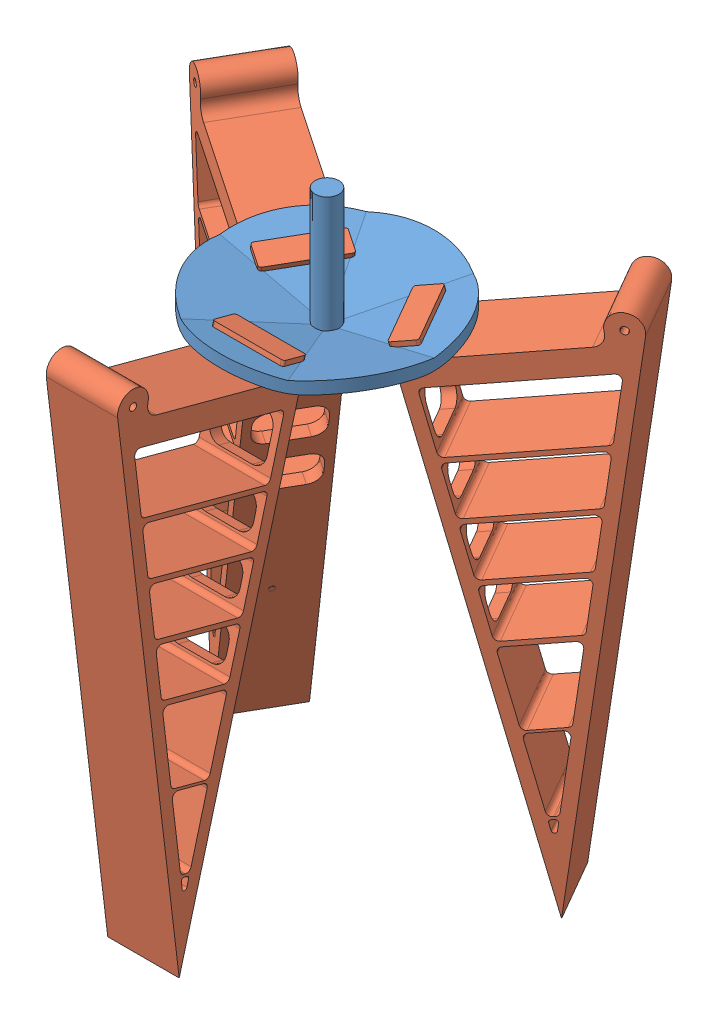
SolidWorks assembly Assem1, configuration Default. Lengths in mm.
Overall size (283.23 241.86 246.25).
4 component instances, 2 part files, 9 mates.
Components (placement in the parent):
- gripper hand-1: gripper hand [Default] at (12.3889 -3.2286 -6.0425) size (90 53.44 90)
- flexable hand-1: flexable hand [Default] at (27.3889 -1.6143 19.3005) x (0 -0.258819 -0.965926) z (0 0.965926 -0.258819) size (81.6 30 211.5)
- flexable hand-2: flexable hand [Default] at (-16.2222 -1.8732 -5.2406) x (0.836516 -0.258819 0.482963) z (0.224144 0.965926 0.12941) size (81.6 30 211.5)
- flexable hand-3: flexable hand [Default] at (26.0001 -1.8732 -31.2214) x (-0.836516 -0.258819 0.482963) z (-0.224144 0.965926 0.12941) size (81.6 30 211.5)
Mates (geometry in assembly coordinates):
- Coincident18: coincident anti-aligned: plane of gripper hand-1 through (36.2584 -15.1704 -37.144) normal (-0.836516 -0.258819 0.482963); plane of flexable hand-3 through (57.2515 5.027 10.041) normal (0.836516 0.258819 -0.482963)
- Coincident19: coincident anti-aligned: plane of gripper hand-1 through (47.0758 -16.4645 -8.7484) normal (-0.5 0 -0.866025); plane of flexable hand-3 through (41.0001 -1.8732 -5.2406) normal (0.5 0 0.866025)
- Coincident20: coincident anti-aligned: plane of gripper hand-1 through (12.3889 -3.2286 -6.0425) normal (-0.224144 0.965926 0.12941); plane of flexable hand-3 through (58.9246 5.5447 9.0751) normal (0.224144 -0.965926 -0.12941)
- Coincident22: coincident anti-aligned: plane of gripper hand-1 through (-2.6111 -12.3467 24.2468) normal (1 0 0); plane of flexable hand-1 through (-2.6111 -1.6143 19.3005) normal (-1 0 0)
- Coincident23: coincident anti-aligned: plane of gripper hand-1 through (27.3889 -12.3467 24.2468) normal (0 0.258819 0.965926); plane of flexable hand-1 through (-23.9711 -1.0967 21.2324) normal (0 -0.258819 -0.965926)
- Coincident24: coincident anti-aligned: plane of gripper hand-1 through (12.3889 -3.2286 -6.0425) normal (0 0.965926 -0.258819); plane of flexable hand-1 through (-23.9711 3.7329 19.9383) normal (0 -0.965926 0.258819)
- Coincident25: coincident anti-aligned: plane of gripper hand-1 through (-26.4805 -15.1704 -11.1632) normal (0.836516 -0.258819 0.482963); plane of flexable hand-2 through (3.8864 5.027 -52.9364) normal (-0.836516 0.258819 -0.482963)
- Coincident26: coincident anti-aligned: plane of gripper hand-1 through (12.3889 -3.2286 -6.0425) normal (0.224144 0.965926 0.12941); plane of flexable hand-2 through (2.2133 5.5447 -53.9023) normal (-0.224144 -0.965926 -0.12941)
- Coincident27: coincident anti-aligned: plane of gripper hand-1 through (-7.2979 -16.4645 -34.7292) normal (-0.5 0 0.866025); plane of flexable hand-2 through (-1.2222 -1.8732 -31.2214) normal (0.5 0 -0.866025)
